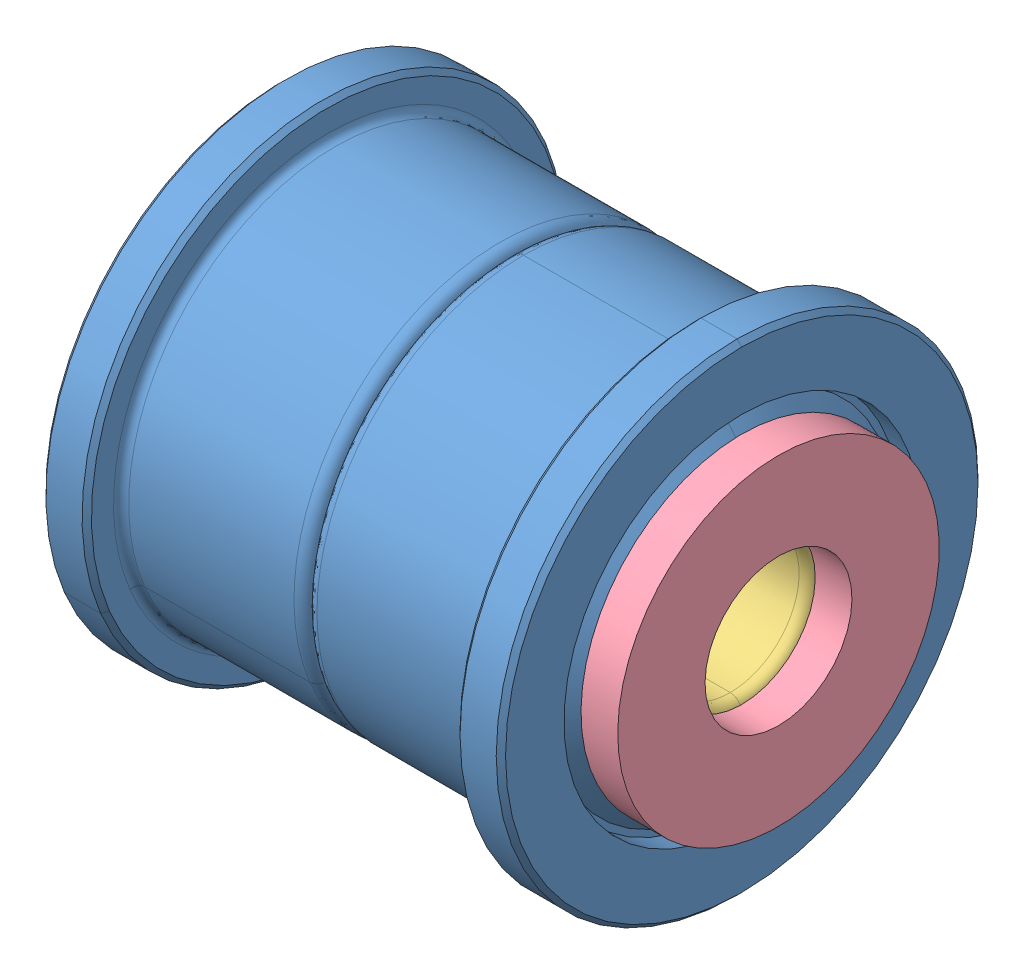
SolidWorks assembly Bearing assembly1, configuration Default. Lengths in mm.
Overall size (10.81 13.72 13.72).
9 component instances, 4 part files, 5 mates.
Components (placement in the parent):
- Idler Bearing (F603HZZ) Assembly-1: Idler Bearing (F603HZZ) Assembly [Default] at (4.8712 0.0732 -2.5403) size (5 10.49 10.49)
  - Idler Bearing (F603HZZ) part 1-1: Idler Bearing (F603HZZ) part 1 [Default] at origin size (5 10.49 10.49)
  - Idler Bearing (F603HZZ) part 2-1: Idler Bearing (F603HZZ) part 2 [Default] at origin size (3.13 7.92 8.2)
  - Idler Bearing (F603HZZ) part 3-1: Idler Bearing (F603HZZ) part 3 [Default] at origin size (5 4.24 4.24)
- Idler Bearing (F603HZZ) Assembly-2: Idler Bearing (F603HZZ) Assembly [Default] at (-0.1326 0.0732 -2.5403) x (-1 0 0) z (0 -0.922978 -0.384852) size (5 10.49 10.49)
  - Idler Bearing (F603HZZ) part 1-1: Idler Bearing (F603HZZ) part 1 [Default] at origin size (5 10.49 10.49)
  - Idler Bearing (F603HZZ) part 2-1: Idler Bearing (F603HZZ) part 2 [Default] at origin size (3.13 7.92 8.2)
  - Idler Bearing (F603HZZ) part 3-1: Idler Bearing (F603HZZ) part 3 [Default] at origin size (5 4.24 4.24)
- plain washer 10673 type snl_iso-1: plain washer 10673 type snl_iso [ISO 10673-3.2-S] at (7.3731 0.0732 -2.5403) x (1 0 0) z (0 0.016518 0.999864) size (0.8 7 7)
Mates (geometry in assembly coordinates):
- Concentric401055: concentric: cylinder of Idler Bearing (F603HZZ) Assembly-1/Idler Bearing (F603HZZ) part 3-1 through (2.1192 0.0732 -2.5403) axis (1 0 0) radius 1.4986; cylinder of Idler Bearing (F603HZZ) Assembly-2/Idler Bearing (F603HZZ) part 3-1 through (2.6195 0.0732 -2.5403) axis (-1 0 0) radius 1.4986
- Coincident7871306: coincident: plane of Idler Bearing (F603HZZ) Assembly-1/Idler Bearing (F603HZZ) part 1-1 through (2.3693 0.0732 -2.5403) normal (-1 0 0); plane of Idler Bearing (F603HZZ) Assembly-2/Idler Bearing (F603HZZ) part 1-1 through (2.3693 0.0732 -2.5403) normal (1 0 0)
- Coincident7871309: coincident: plane of Idler Bearing (F603HZZ) Assembly-1/Idler Bearing (F603HZZ) part 1-1 through (7.2731 0.0732 -2.5403) normal (1 0 0); plane of plain washer 10673 type snl_iso-1 through (7.3731 0.0732 -2.5403) normal (-1 0 0)
- Concentric401056: concentric: cylinder of Idler Bearing (F603HZZ) Assembly-1/Idler Bearing (F603HZZ) part 3-1 through (2.1192 0.0732 -2.5403) axis (1 0 0) radius 1.4986; cylinder of plain washer 10673 type snl_iso-1 through (8.1731 0.0732 -2.5403) axis (-1 0 0) radius 1.6
- Coincident7871310: coincident: plane of Idler Bearing (F603HZZ) Assembly-1/Idler Bearing (F603HZZ) part 3-1 through (7.3731 0.0732 -2.5403) normal (1 0 0); plane of plain washer 10673 type snl_iso-1 through (7.3731 0.0732 -2.5403) normal (-1 0 0)
